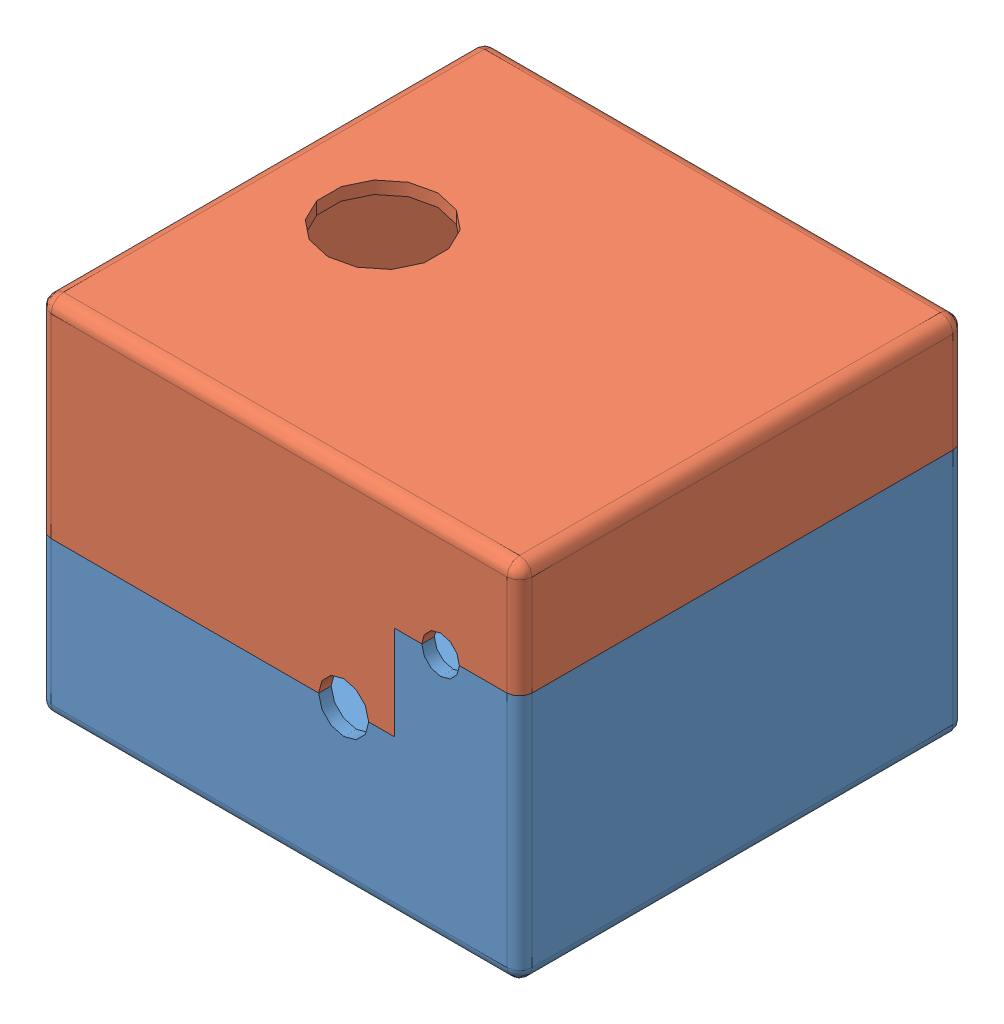
SolidWorks assembly Assem1, configuration Default. Lengths in mm.
Overall size (96 72.5 89).
2 component instances, 2 part files, 10 mates.
Components (placement in the parent):
- controller_case_bottom_V3_1212-1: controller_case_bottom_V3_1212 [Default] at (-7.3354 22.9315 28.1282) size (96 49.95 89)
- controller_case_top_V3_1212-2: controller_case_top_V3_1212 [Default] at (-7.3354 95.4315 117.1282) x (1 0 0) z (0 0 -1) size (96 63 89)
Mates (geometry in assembly coordinates):
- Parallel3: parallel: plane of controller_case_bottom_V3_1212-1 through (-7.3354 25.4315 28.1282) normal (0 1 0); plane of controller_case_top_V3_1212-2 through (-7.3354 92.9315 117.435) normal (0 -1 0)
- Coincident7: coincident: plane of controller_case_bottom_V3_1212-1 through (-7.3354 95.4315 28.1282) normal (-1 0 0); plane of controller_case_top_V3_1212-2 through (-7.3354 22.9315 117.435) normal (-1 0 0)
- Parallel4: parallel: plane of controller_case_bottom_V3_1212-1 through (-7.3354 95.4315 117.1282) normal (0 0 1); plane of controller_case_top_V3_1212-2 through (-7.3354 22.9315 117.435) normal (0 0 1)
- Parallel5: parallel: plane of controller_case_bottom_V3_1212-1 through (-7.3354 95.4315 28.1282) normal (0 0 -1); plane of controller_case_top_V3_1212-2 through (-7.3354 22.9315 28.435) normal (0 0 -1)
- Parallel6: parallel: plane of controller_case_bottom_V3_1212-1 through (-7.3354 95.4315 28.1282) normal (-1 0 0); plane of controller_case_top_V3_1212-2 through (-7.3354 22.9315 117.435) normal (-1 0 0)
- Parallel7: parallel: plane of controller_case_bottom_V3_1212-1 through (88.6646 95.4315 28.1282) normal (1 0 0); plane of controller_case_top_V3_1212-2 through (88.6646 22.9315 117.435) normal (1 0 0)
- Coincident12: coincident: plane of controller_case_bottom_V3_1212-1 through (88.6646 72.8815 28.1282) normal (0 1 0); plane of controller_case_top_V3_1212-2 through (88.6646 72.8815 28.435) normal (0 -1 0)
- Coincident13: coincident: plane of controller_case_bottom_V3_1212-1 through (63.6646 54.0915 28.1282) normal (0 1 0); plane of controller_case_top_V3_1212-2 through (63.6646 54.0915 28.435) normal (0 -1 0)
- Coincident14: coincident: plane of controller_case_bottom_V3_1212-1 through (63.6646 32.4315 30.6282) normal (0 1 0); plane of controller_case_top_V3_1212-2 through (21.6646 32.4315 30.935) normal (0 -1 0)
- Distance1: distance = 0 mm aligned: plane of controller_case_top_V3_1212-2 through (-7.3354 22.9315 28.1282) normal (0 0 -1); plane of controller_case_bottom_V3_1212-1 through (-7.3354 95.4315 28.1282) normal (0 0 -1)
